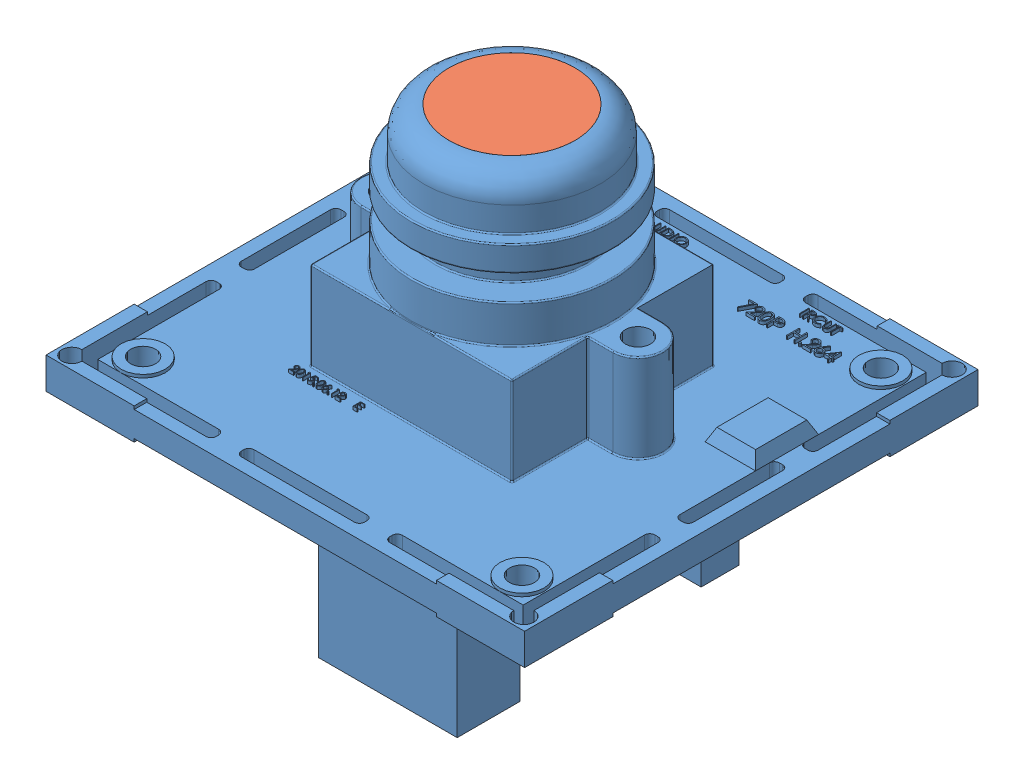
SolidWorks assembly Assem1cam, configuration Default. Lengths in mm.
Overall size (38 30 36).
2 component instances, 2 part files, 4 mates.
Components (placement in the parent):
- Part1-1: Part1 [Default] at (-34.3917 19.0361 1.8182) size (38 30 36)
- Part2-1: Part2 [Default] at (-34.3917 38.0361 1.8182) x (1 0 0) z (0 1 0) size (10 10 1)
Mates (geometry in assembly coordinates):
- InPlace1: in place: plane of Part1-1 through (-34.3917 38.0361 1.8182) normal (0 1 0); plane of ? through (0 38.0361 0) normal (0 1 0); moOrthogonalPlaneRef_w of Part1-1 through (-34.3917 38.0361 1.8182) normal (0 1 0); plane of ? through (0 38.0361 0) normal (0 0 -1); plane of Part1-1 through (-34.3917 38.0361 1.8182) normal (0 1 0); line of ? through (-55 0 38.0361) axis (0 1 0); plane of Part1-1 through (-34.3917 38.0361 1.8182) normal (0 1 0); unknown of Part2-1
- Coincident1: coincident aligned: plane of Part1-1; plane of Part2-1
- Coincident2: coincident aligned: moOrthogonalPlaneRef_w of Part1-1 through (-34.3917 38.0361 1.8182) normal (0 0 -1); plane of Part2-1 through (-34.3917 38.0361 1.8182) normal (0 0 -1)
- Coincident3: coincident anti-aligned: moOrthogonalPlaneRef_w of Part1-1 through (-34.3917 38.0361 1.8182) normal (-1 0 0); plane of Part2-1
